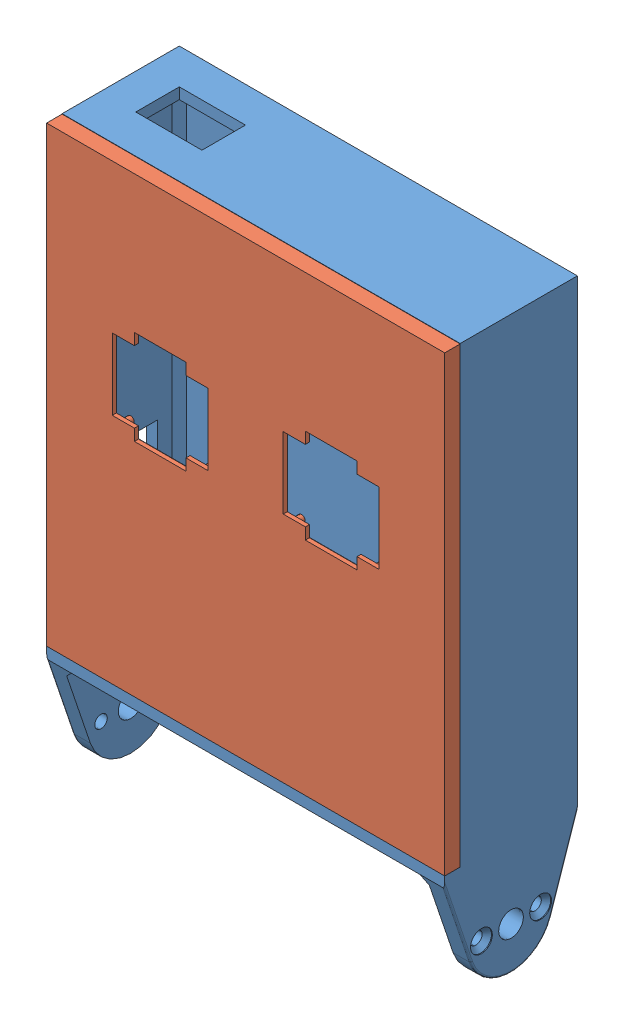
SolidWorks assembly Igor, configuration Default. Lengths in mm.
Overall size (114.3 163.83 38.1).
2 component instances, 2 part files, 3 mates.
Components (placement in the parent):
- SlimFrame-1: SlimFrame [Default] at (103.037 165.6919 56.7123) x (-1 0 0) z (0 0 1) size (114.3 163.83 38.1)
- BreadboardWall-1: BreadboardWall [Default] at (103.037 295.7653 74.1748) x (-1 0 0) z (0 0 1) size (114.3 130.07 11.45)
Mates (geometry in assembly coordinates):
- Coincident8: coincident: plane of SlimFrame-1 through (103.037 165.6919 56.7123) normal (0 1 0); plane of BreadboardWall-1 through (103.037 165.6919 74.1748) normal (0 -1 0)
- Coincident9: coincident: plane of SlimFrame-1 through (45.887 162.5169 37.6623) normal (-1 0 0); plane of BreadboardWall-1 through (45.887 165.6919 75.7623) normal (-1 0 0)
- Coincident10: coincident: plane of SlimFrame-1 through (103.037 292.6919 71.3173) normal (0 0 1); plane of BreadboardWall-1 through (103.037 295.7653 71.3173) normal (0 0 -1)
